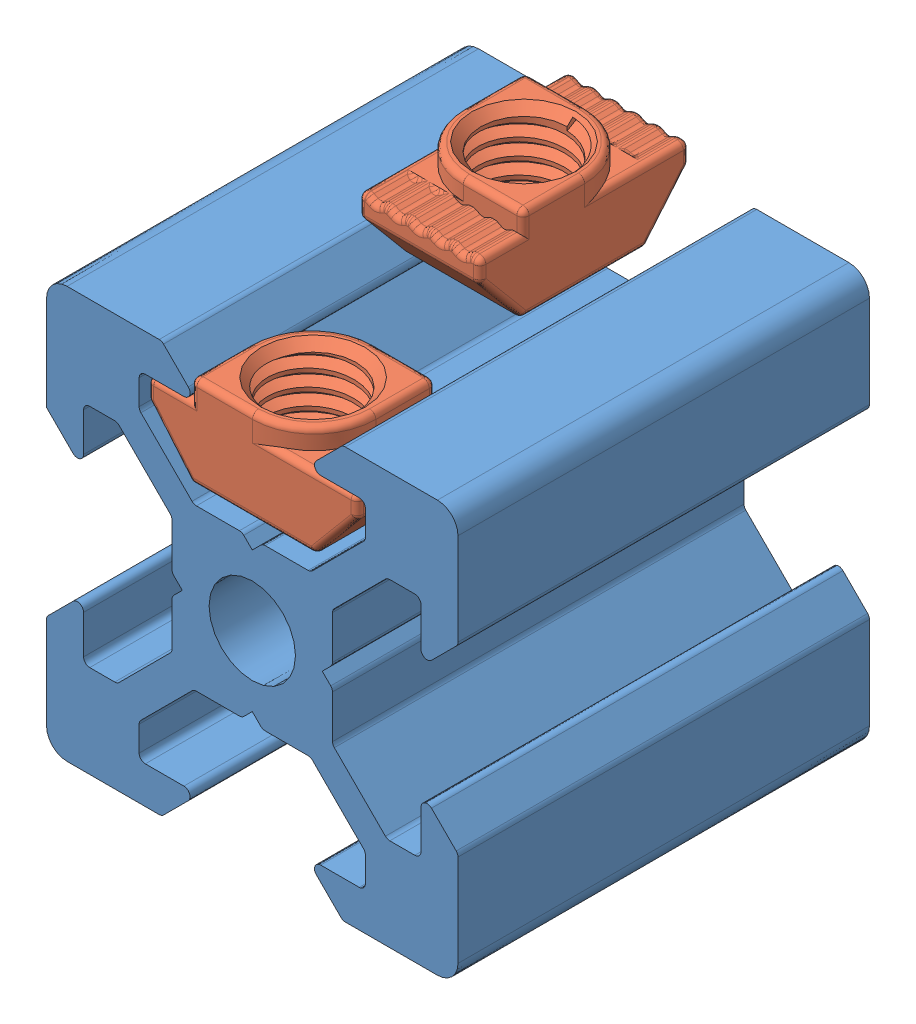
SolidWorks assembly Сборка Т-Гайка 6 паз, configuration По умолчанию. Lengths in mm.
Overall size (20 24.03 20).
3 component instances, 2 part files, 4 mates.
Components (placement in the parent):
- 2020V-1: 2020V [По умолчанию] at origin size (20 20 20)
- Т-Гайка 6 паз-1: Т-Гайка 6 паз [По умолчанию] at (0.0077 4.7 17.05) size (10.2 4.61 5.9)
- Т-Гайка 6 паз-2: Т-Гайка 6 паз [По умолчанию] at (0.0287 9.5211 6.8207) x (0 0 -1) z (1 0 0) size (10.2 4.61 5.9)
Mates (geometry in assembly coordinates):
- Совпадение1: coincident: plane of 2020V-1 through (-2.6 8.2 20) normal (0 -1 0); plane of Т-Гайка 6 паз-1 through (-5.0923 8.2 12.7786) normal (0 1 0)
- Параллельность1: parallel: plane of 2020V-1 through (-10 10 20) normal (0 1 0); plane of Т-Гайка 6 паз-2 through (-6.5369 18.8459 7.1596) normal (0 1 0)
- Параллельность2: parallel aligned: plane of 2020V-1 through (10 10 20) normal (1 0 0); plane of Т-Гайка 6 паз-2 through (-0.6369 14.3459 4.1596) normal (1 0 0)
- Совпадение4: coincident aligned: plane of 2020V-1 through (0 0 20) normal (0 0 1); plane of Т-Гайка 6 паз-1 through (0.0077 4.7 20) normal (0 0 1)
